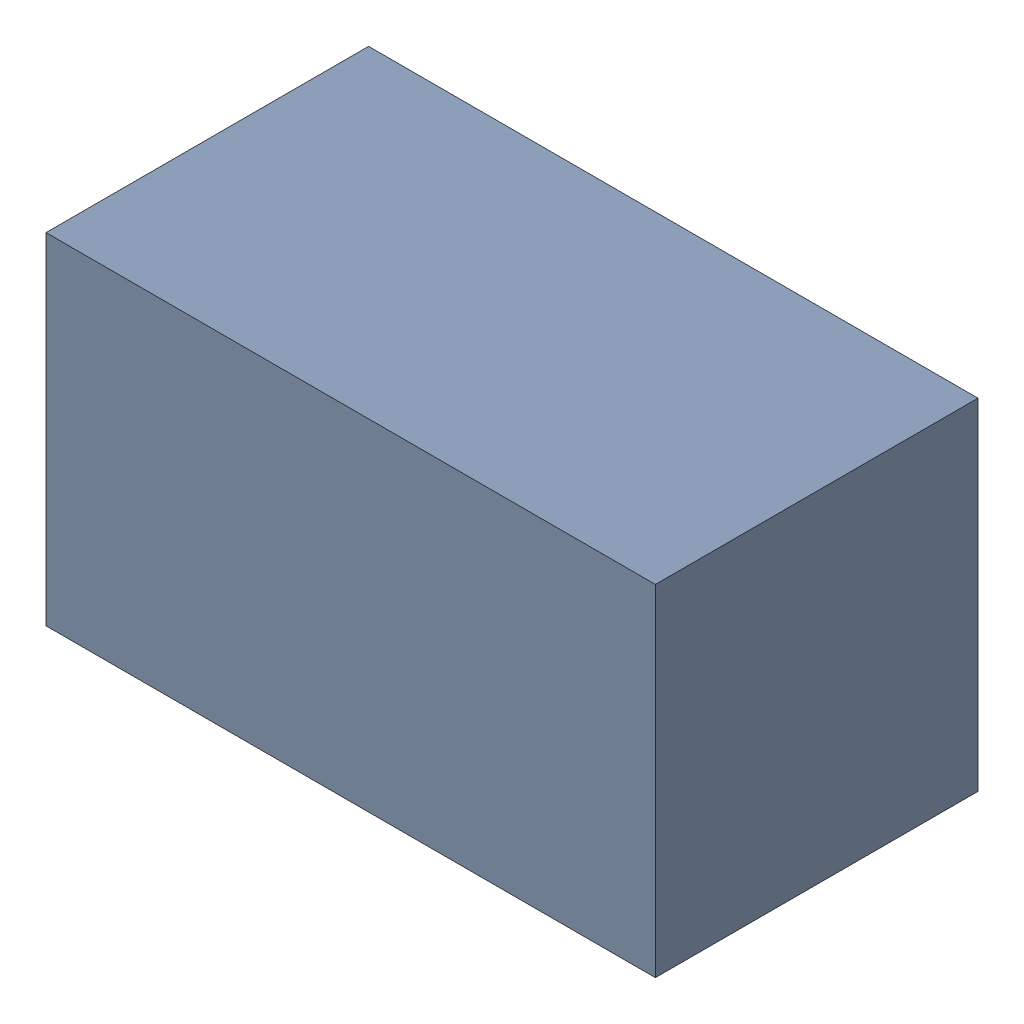
SolidWorks assembly R21, configuration Standard. Lengths in mm.
Overall size (1.7 0.95 0.9).
2 component instances, 1 part files, 0 mates.
Components (placement in the parent):
- 885541288-1: 885541288 [Standard] at (15.46 23.41 0) size (1.7 0.95 0.9)
  - Extruded_10-1: Extruded_10 [Standard] at origin size (1.7 0.95 0.9)
